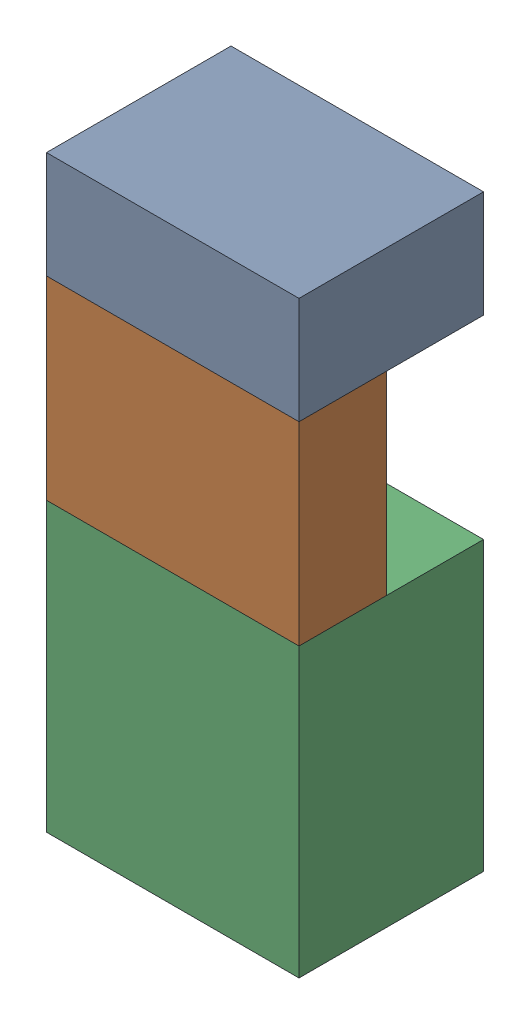
SolidWorks assembly SUP_K17, configuration Default. Lengths in mm.
Overall size (13 30.3 9.5).
6 component instances, 3 part files, 0 mates.
Components (placement in the parent):
- 1151724928-1: 1151724928 [Default] at (260.985 41.975 0) size (13 5.5 9.5)
  - Extruded_2-1: Extruded_2 [Default] at origin size (13 5.5 9.5)
- 1151725064-1: 1151725064 [Default] at (260.985 34.225 5) size (13 10 4.5)
  - Extruded_3-1: Extruded_3 [Default] at origin size (13 10 4.5)
- 1151724792-1: 1151724792 [Default] at (260.985 21.825 0) size (13 14.8 9.5)
  - Extruded_4-1: Extruded_4 [Default] at origin size (13 14.8 9.5)
